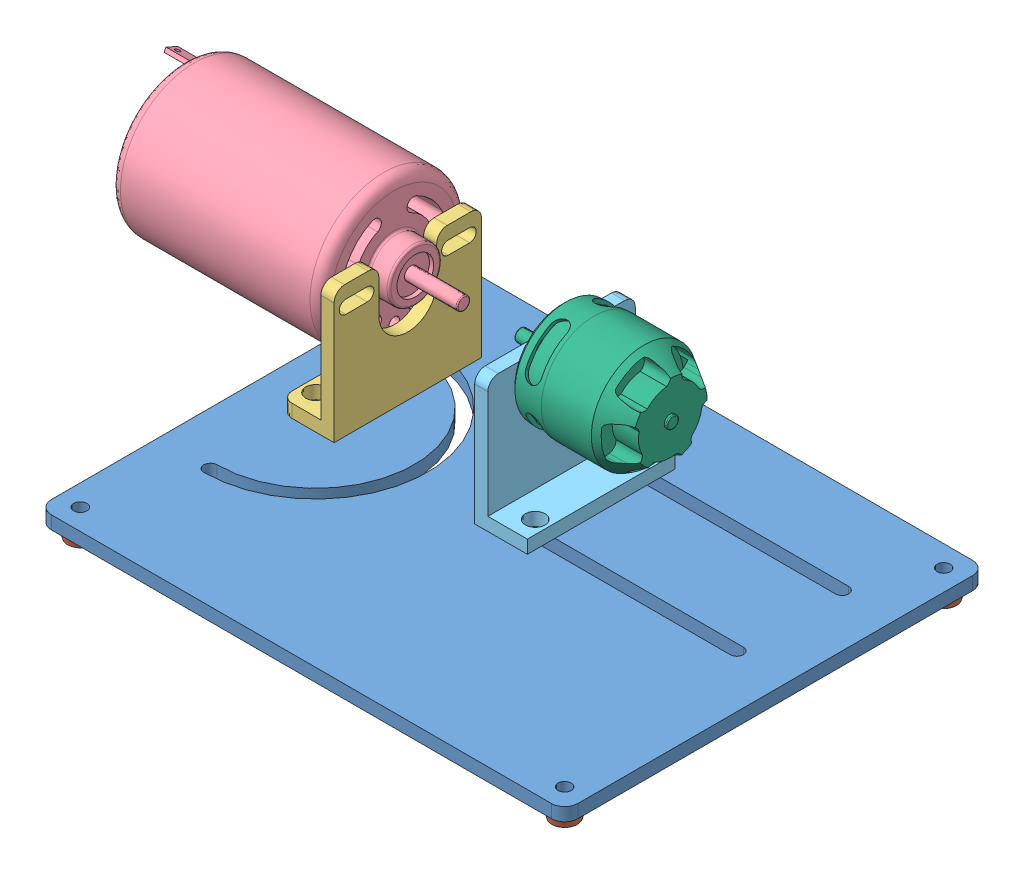
SolidWorks assembly Dyno_assem, configuration Default. Lengths in mm.
Overall size (167.01 56.96 101.6).
9 component instances, 6 part files, 21 mates.
Components (placement in the parent):
- Dyno base plate-1: Dyno base plate [Default] at (-17.3389 70.0779 129.0649) size (127 3.17 101.6)
- dyno_foot-1: dyno_foot [Default] at (-12.2589 66.9029 123.9849) x (0.998739 0 -0.050195) z (0.050195 0 0.998739) size (7.11 3.17 7.11)
- dyno_foot-2: dyno_foot [Default] at (104.5811 66.9029 123.9849) size (7.11 3.17 7.11)
- dyno_foot-3: dyno_foot [Default] at (104.5811 66.9029 32.5449) size (7.11 3.17 7.11)
- dyno_foot-4: dyno_foot [Default] at (-12.2589 66.9029 32.5449) size (7.11 3.17 7.11)
- Generator_motor_mount-1: Generator_motor_mount [Default] at (-1.4639 73.2529 62.1358) x (0 0 -1) z (0 1 0) size (35.56 12.7 31.75)
- Dyno_generator-1: Dyno_generator [Default] at (-49.0889 100.2404 62.2276) x (0 0.906684 -0.421811) z (1 0 0) size (35.56 35.56 75.82)
- Large_motor_mount_dyno-1: Large_motor_mount_dyno [Default] at (45.1623 73.2529 62.1358) x (0 0 1) z (0 1 0) size (35.56 12.7 31.75)
- med_motor-1: med_motor [Default] at (61.6723 100.3747 61.9455) x (0 -0.702198 0.711981) z (-1 0 0) size (25.4 25.4 36.83)
Mates (geometry in assembly coordinates):
- Concentric1: concentric anti-aligned: circle of Dyno base plate-1; circle of dyno_foot-1
- Concentric2: concentric anti-aligned: circle of Dyno base plate-1; circle of dyno_foot-4
- Concentric3: concentric aligned: cylinder of Dyno base plate-1 through (104.5811 73.2529 123.9849) axis (0 -1 0) radius 1.5875; cylinder of dyno_foot-2 through (104.5811 66.9029 123.9849) axis (0 -1 0) radius 1.524
- Concentric4: concentric aligned: cylinder of Dyno base plate-1 through (104.5811 73.2529 32.5449) axis (0 -1 0) radius 1.5875; cylinder of dyno_foot-3 through (104.5811 66.9029 32.5449) axis (0 -1 0) radius 1.524
- Coincident1: coincident anti-aligned: plane of Dyno base plate-1 through (-17.3389 70.0779 129.0649) normal (0 -1 0); plane of dyno_foot-3 through (106.1051 70.0779 32.5449) normal (0 1 0)
- Coincident2: coincident anti-aligned: plane of Dyno base plate-1 through (-17.3389 70.0779 129.0649) normal (0 -1 0); plane of dyno_foot-2 through (106.1051 70.0779 123.9849) normal (0 1 0)
- Coincident3: coincident anti-aligned: plane of Dyno base plate-1 through (-17.3389 70.0779 129.0649) normal (0 -1 0); plane of dyno_foot-1 through (-10.7369 70.0779 123.9084) normal (0 1 0)
- Coincident4: coincident anti-aligned: plane of Dyno base plate-1 through (-17.3389 70.0779 129.0649) normal (0 -1 0); plane of dyno_foot-4 through (-10.7349 70.0779 32.5449) normal (0 1 0)
- Coincident5: coincident anti-aligned: plane of Dyno base plate-1 through (-17.3389 73.2529 129.0649) normal (0 1 0); plane of Generator_motor_mount-1 through (-1.4639 73.2529 62.1358) normal (0 -1 0)
- Concentric10: concentric aligned: cylinder of Dyno base plate-1 through (-4.6389 73.2529 74.8358) axis (0 -1 0) radius 1.5875; cylinder of Generator_motor_mount-1 through (-4.6389 76.4279 74.8358) axis (0 -1 0) radius 2.3813
- Hinge1: hinge = 3.141593 rad aligned: cylinder of Generator_motor_mount-1 through (-4.6389 76.4279 74.8358) axis (0 -1 0) radius 2.3813; cylinder of Dyno base plate-1 through (-4.6389 73.2529 74.8358) axis (0 -1 0) radius 1.5875; plane of Dyno base plate-1 through (-17.3389 73.2529 129.0649) normal (0 1 0); plane of Generator_motor_mount-1 through (-1.4639 73.2529 62.1358) normal (0 1 0); plane of Generator_motor_mount-1 through (4.8861 76.4279 79.9158) normal (1 0 0); plane of Dyno base plate-1 through (-17.3389 73.2529 129.0649) normal (-1 0 0)
- Tangent1: tangent anti-aligned: plane of Generator_motor_mount-1 through (-23.6889 98.6529 77.0746) normal (0 1 0); cylinder of Dyno_generator-1 through (-23.6889 100.2404 73.3401) axis (1 0 0) radius 1.5875
- Tangent2: tangent anti-aligned: plane of Generator_motor_mount-1 through (-23.6889 98.6529 47.197) normal (0 1 0); cylinder of Dyno_generator-1 through (-23.6889 100.2404 51.1151) axis (1 0 0) radius 1.5875
- Coincident6: coincident anti-aligned: plane of Generator_motor_mount-1 through (1.7111 105.0029 79.9158) normal (-1 0 0); plane of Dyno_generator-1 through (1.7111 100.2404 62.2276) normal (1 0 0)
- Slot1: slot aligned: cylinder of Dyno_generator-1 through (-23.6889 100.2404 51.1151) axis (1 0 0) radius 1.5875; plane of Generator_motor_mount-1 through (-23.6889 98.6529 47.197) normal (0 1 0); cylinder of Generator_motor_mount-1 through (-23.6889 100.2404 52.3851) axis (1 0 0) radius 1.5875
- Coincident7: coincident anti-aligned: plane of Dyno base plate-1 through (-17.3389 73.2529 129.0649) normal (0 1 0); plane of Large_motor_mount_dyno-1 through (45.1623 73.2529 62.1358) normal (0 -1 0)
- Slot2: slot aligned: cylinder of Large_motor_mount_dyno-1 through (48.5632 76.4279 74.8351) axis (0 -1 0) radius 2.3813; plane of Dyno base plate-1 through (-17.3389 73.2529 76.4233) normal (0 0 -1); cylinder of Dyno base plate-1 through (46.1611 73.2529 74.8358) axis (0 -1 0) radius 1.5875
- Slot3: slot aligned: cylinder of Large_motor_mount_dyno-1 through (48.3371 76.4279 49.4361) axis (0 -1 0) radius 2.3813; plane of Dyno base plate-1 through (-17.3389 73.2529 51.0233) normal (0 0 -1); cylinder of Dyno base plate-1 through (46.1611 73.2529 49.4358) axis (0 -1 0) radius 1.5875
- Concentric11: concentric aligned: cylinder of Large_motor_mount_dyno-1 through (51.5123 100.4309 70.0733) axis (-1 0 0) radius 1.1906; cylinder of med_motor-1 through (47.0673 100.4309 70.0733) axis (-1 0 0) radius 1.5875
- Coincident8: coincident anti-aligned: plane of Large_motor_mount_dyno-1 through (41.9873 105.0029 44.3558) normal (1 0 0); plane of med_motor-1 through (41.9873 91.8135 70.626) normal (-1 0 0)
- Tangent6: tangent aligned: cylinder of Large_motor_mount_dyno-1 through (51.5123 100.4309 54.1983) axis (-1 0 0) radius 1.1906; cylinder of med_motor-1 through (47.0673 100.3185 53.8177) axis (-1 0 0) radius 1.5875
